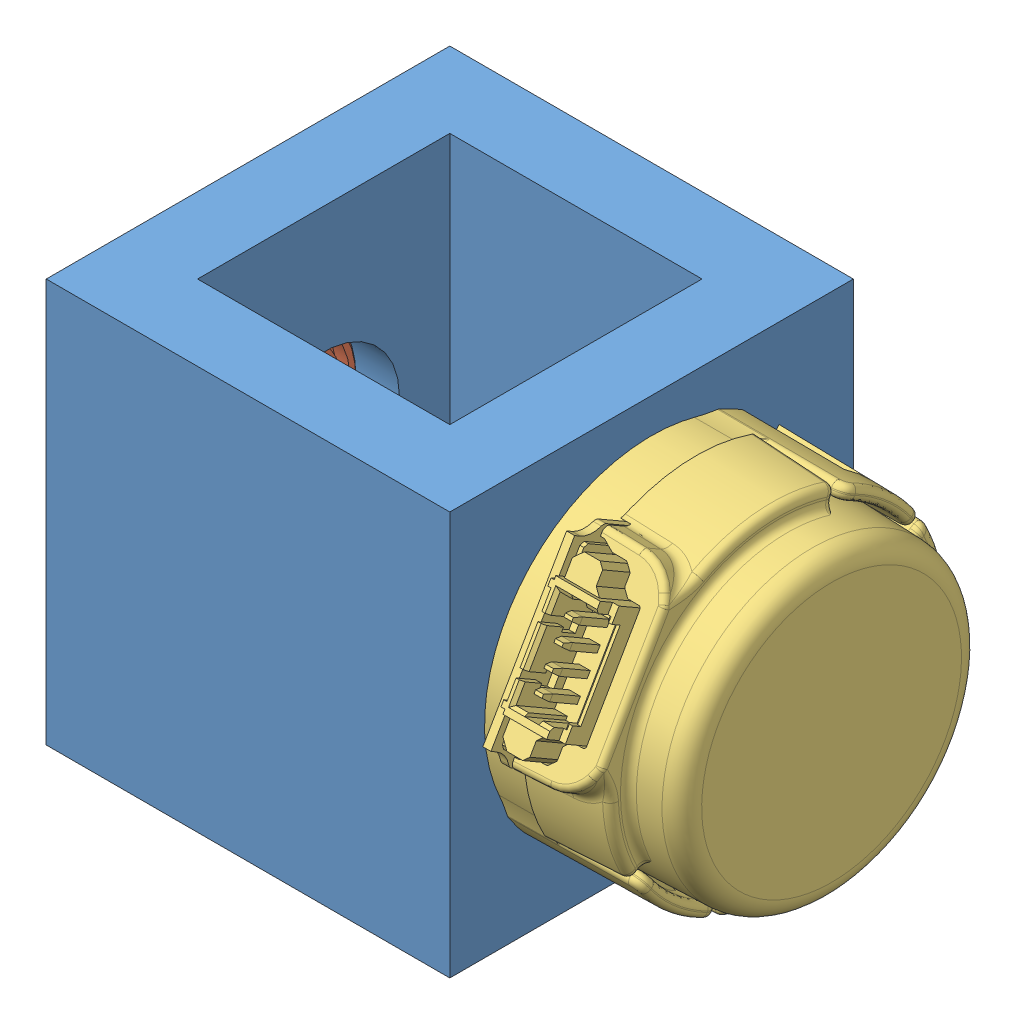
SolidWorks assembly EncoderBlock, configuration Default. Lengths in mm.
Overall size (37.74 31.82 30.88).
4 component instances, 3 part files, 7 mates.
Components (placement in the parent):
- BearingBlock-1: BearingBlock [Default] at (-16.3048 -10.4057 15.6733) size (25.4 25.4 25.4)
- BallBearing-1: BallBearing [57155K322] at (-15.7333 2.2943 2.9733) x (0 0 -1) z (1 0 0) size (10.72 10.72 3.17)
- BallBearing-2: BallBearing [57155K322] at (4.9042 2.2943 2.9733) x (0 0 -1) z (1 0 0) size (10.72 10.72 3.17)
- E4P-X-250-X-S-D-D-X-1: E4P-X-250-X-S-D-D-X [Default] at (9.0952 2.2943 2.9733) x (0 -0.866025 -0.5) z (0 -0.5 0.866025) size (24.23 14.38 21.67)
Mates (geometry in assembly coordinates):
- Coincident1: coincident anti-aligned: plane of BearingBlock-1 through (-16.3048 14.9943 15.6733) normal (-1 0 0); plane of BallBearing-1 through (-16.3048 6.7202 2.9733) normal (1 0 0)
- Concentric1: concentric anti-aligned: circle of BearingBlock-1; circle of BallBearing-1
- Coincident2: coincident anti-aligned: plane of BearingBlock-1 through (4.3327 -10.4057 10.9108) normal (-1 0 0); plane of BallBearing-2 through (4.3327 6.7202 2.9733) normal (1 0 0)
- Concentric2: concentric anti-aligned: circle of BearingBlock-1; circle of BallBearing-2
- Concentric4: concentric aligned: circle of E4P-X-250-X-S-D-D-X-1; circle of BearingBlock-1
- Concentric5: concentric aligned: circle of BearingBlock-1; circle of E4P-X-250-X-S-D-D-X-1
- Coincident5: coincident anti-aligned: plane of BearingBlock-1 through (9.0952 14.9943 15.6733) normal (1 0 0); plane of E4P-X-250-X-S-D-D-X-1 through (9.0952 2.2943 2.9733) normal (-1 0 0)
